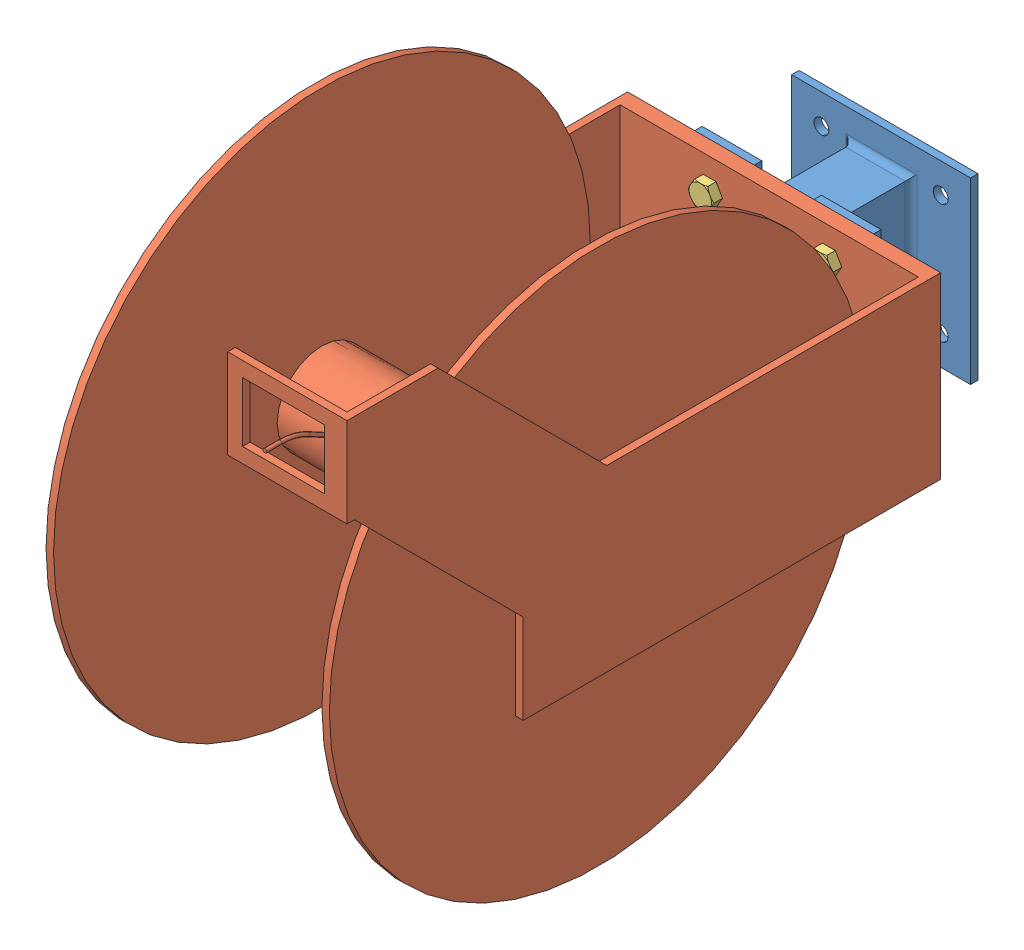
SolidWorks assembly Retraction Reel Subassembly, configuration Default. Lengths in mm.
Overall size (266.7 457.2 628.3).
10 component instances, 4 part files, 27 mates.
Components (placement in the parent):
- Retraction Bracket-1: Retraction Bracket [Default] at (-13.9214 19.9743 58.3774) size (152.4 152.4 88.9)
- Retraction Reel-1: Retraction Reel [Default] at (-58.3714 96.1743 426.6774) size (266.7 457.2 539.4)
- 1-2 inch x 1 inch SS, 1-2-20-1: 1-2 inch x 1 inch SS, 1-2-20 [92240A432] at (113.0786 146.9743 151.2462) x (0 0 -1) z (0.866025 0.5 0) size (33.84 22 19.05)
- 1-2-20 SS Nut-1: 1-2-20 SS Nut [93839A825] at (113.0786 146.9743 136.9587) x (1 0 0) z (0 -1 0) size (19.05 8.94 22)
- 1-2 inch x 1 inch SS, 1-2-20-2: 1-2 inch x 1 inch SS, 1-2-20 [92240A432] at (113.0786 45.3743 151.2462) x (0 0 -1) z (0 1 0) size (33.84 22 19.05)
- 1-2 inch x 1 inch SS, 1-2-20-3: 1-2 inch x 1 inch SS, 1-2-20 [92240A432] at (11.4786 146.9743 151.2462) x (0 0 -1) z (0.866025 0.5 0) size (33.84 22 19.05)
- 1-2 inch x 1 inch SS, 1-2-20-4: 1-2 inch x 1 inch SS, 1-2-20 [92240A432] at (11.4786 45.3743 151.2462) x (0 0 -1) z (0.866025 0.5 0) size (33.84 22 19.05)
- 1-2-20 SS Nut-2: 1-2-20 SS Nut [93839A825] at (11.4786 146.9743 136.9587) x (0.866025 0.5 0) z (0.5 -0.866025 0) size (19.05 8.94 22)
- 1-2-20 SS Nut-3: 1-2-20 SS Nut [93839A825] at (11.4786 45.3743 136.9587) x (0.866025 0.5 0) z (0.5 -0.866025 0) size (19.05 8.94 22)
- 1-2-20 SS Nut-4: 1-2-20 SS Nut [93839A825] at (113.0786 45.3743 136.9587) x (0.866025 -0.5 0) z (-0.5 -0.866025 0) size (19.05 8.94 22)
Mates (geometry in assembly coordinates):
- Coincident1: coincident anti-aligned: plane of Retraction Bracket-1 through (-13.9214 19.9743 147.2774) normal (0 0 1); plane of Retraction Reel-1 through (189.2786 172.3743 147.2774) normal (0 0 -1)
- Coincident2: coincident anti-aligned: circle of Retraction Bracket-1; circle of Retraction Reel-1
- Coincident3: coincident anti-aligned: circle of Retraction Bracket-1; circle of Retraction Reel-1
- Coincident4: coincident anti-aligned: plane of Retraction Reel-1 through (-216.8874 172.3743 159.9774) normal (0 0 1); plane of 1-2 inch x 1 inch SS, 1-2-20-1 through (118.5778 156.4993 159.9774) normal (0 0 -1)
- Tangent1: tangent: cylinder of Retraction Bracket-1 through (113.0786 146.9743 147.2774) axis (0 0 -1) radius 6.35; curve of 1-2 inch x 1 inch SS, 1-2-20-1
- Coincident5: coincident anti-aligned: plane of Retraction Bracket-1 through (-13.9214 19.9743 140.9274) normal (0 0 -1); plane of 1-2-20 SS Nut-1 through (103.5536 152.4736 140.9274) normal (0 0 1)
- Parallel1: parallel aligned: plane of 1-2 inch x 1 inch SS, 1-2-20-1 through (113.0786 146.9743 134.5774) normal (0 0 -1); plane of 1-2-20 SS Nut-1 through (103.5536 152.4736 132.9899) normal (0 0 -1)
- Concentric1: concentric aligned: circle of 1-2 inch x 1 inch SS, 1-2-20-1; circle of 1-2-20 SS Nut-1
- Coincident8: coincident anti-aligned: plane of Retraction Reel-1 through (-216.8874 172.3743 159.9774) normal (0 0 1); plane of 1-2 inch x 1 inch SS, 1-2-20-3 through (16.9778 156.4993 159.9774) normal (0 0 -1)
- Coincident9: coincident anti-aligned: plane of Retraction Reel-1 through (-216.8874 172.3743 159.9774) normal (0 0 1); plane of 1-2 inch x 1 inch SS, 1-2-20-2 through (107.5793 54.8993 159.9774) normal (0 0 -1)
- Coincident10: coincident anti-aligned: plane of Retraction Reel-1 through (-216.8874 172.3743 159.9774) normal (0 0 1); plane of 1-2 inch x 1 inch SS, 1-2-20-4 through (16.9778 54.8993 159.9774) normal (0 0 -1)
- Concentric2: concentric aligned: circle of Retraction Reel-1; circle of 1-2 inch x 1 inch SS, 1-2-20-3
- Concentric3: concentric aligned: circle of Retraction Reel-1; circle of 1-2 inch x 1 inch SS, 1-2-20-4
- Concentric4: concentric aligned: circle of Retraction Reel-1; circle of 1-2 inch x 1 inch SS, 1-2-20-2
- Parallel3: parallel aligned: plane of Retraction Reel-1 through (195.6286 172.3743 431.7059) normal (0 1 0); plane of 1-2 inch x 1 inch SS, 1-2-20-1 through (118.5778 156.4993 167.9149) normal (0 1 0)
- Parallel4: parallel aligned: plane of Retraction Reel-1 through (195.6286 172.3743 431.7059) normal (0 1 0); plane of 1-2 inch x 1 inch SS, 1-2-20-3 through (16.9778 156.4993 167.9149) normal (0 1 0)
- Parallel5: parallel aligned: plane of Retraction Reel-1 through (195.6286 172.3743 431.7059) normal (0 1 0); plane of 1-2 inch x 1 inch SS, 1-2-20-4 through (16.9778 54.8993 167.9149) normal (0 1 0)
- Parallel6: parallel aligned: plane of Retraction Reel-1 through (195.6286 172.3743 431.7059) normal (0 1 0); plane of 1-2 inch x 1 inch SS, 1-2-20-2 through (118.5778 54.8993 167.9149) normal (0 1 0)
- Coincident11: coincident anti-aligned: plane of Retraction Bracket-1 through (-13.9214 19.9743 140.9274) normal (0 0 -1); plane of 1-2-20 SS Nut-4 through (107.5793 54.8993 140.9274) normal (0 0 1)
- Concentric5: concentric anti-aligned: circle of 1-2 inch x 1 inch SS, 1-2-20-2; circle of 1-2-20 SS Nut-4
- Parallel9: parallel aligned: plane of Retraction Bracket-1 through (87.6786 19.9743 147.2774) normal (0 -1 0); plane of 1-2-20 SS Nut-4 through (107.5793 35.8493 140.9274) normal (0 -1 0)
- Coincident14: coincident anti-aligned: plane of Retraction Bracket-1 through (-13.9214 19.9743 140.9274) normal (0 0 -1); plane of 1-2-20 SS Nut-2 through (0.4801 146.9743 140.9274) normal (0 0 1)
- Concentric7: concentric anti-aligned: circle of 1-2 inch x 1 inch SS, 1-2-20-3; circle of 1-2-20 SS Nut-2
- Parallel10: parallel aligned: plane of Retraction Bracket-1 through (-13.9214 172.3743 147.2774) normal (0 1 0); plane of 1-2-20 SS Nut-2 through (16.9778 156.4993 140.9274) normal (0 1 0)
- Coincident15: coincident anti-aligned: plane of Retraction Bracket-1 through (-13.9214 19.9743 140.9274) normal (0 0 -1); plane of 1-2-20 SS Nut-3 through (0.4801 45.3743 140.9274) normal (0 0 1)
- Concentric8: concentric anti-aligned: circle of 1-2 inch x 1 inch SS, 1-2-20-4; circle of 1-2-20 SS Nut-3
- Parallel11: parallel aligned: plane of Retraction Bracket-1 through (-13.9214 19.9743 147.2774) normal (0 -1 0); plane of 1-2-20 SS Nut-3 through (5.9793 35.8493 140.9274) normal (0 -1 0)
